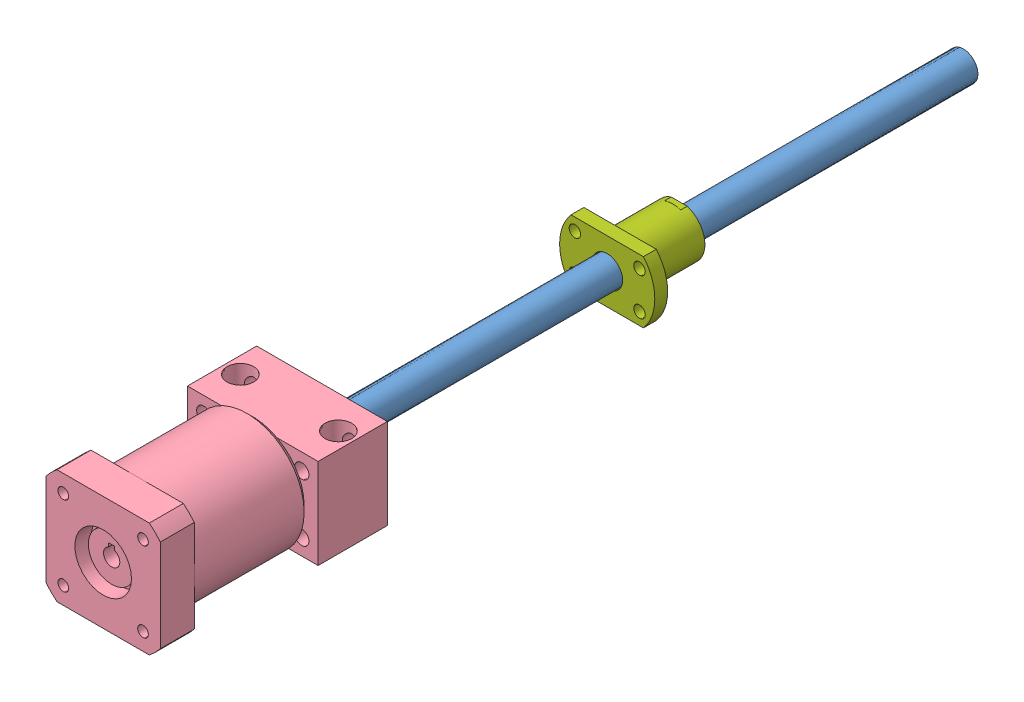
SolidWorks assembly PMBS12x5R_3FW_0_T10_U1_00_300_0_S, configuration Valor predeterminado. Lengths in mm.
Overall size (50.8 44.45 334.47).
8 component instances, 7 part files, 3 mates.
Components (placement in the parent):
- Screw_PMBS 12x5R-1: Screw_PMBS 12x5R [Valor predeterminado] at (0 0 -368.25) size (11.33 11.33 249)
- EndCode1_8-U1-1: EndCode1_8-U1 [Valor predeterminado] at (0 0 -119.25) x (0 0 1) z (-1 0 0) size (85.47 44.45 50.8)
  - Place Holder-1: Place Holder [Valor predeterminado] at origin size (0.38 0.51 0.51)
  - EndMachining_8-3K-1: EndMachining_8-3K [Valor predeterminado] x (0 0 1) z (-1 0 0) size (8 8 50.8)
  - EZM_EZM-1008-17-1: EZM_EZM-1008-17 [Valor predeterminado] at (27.305 -17.4498 25.4) x (0 0 -1) z (1 0 0) size (50.8 44.45 85.09)
  - LockNut(1)_N-00.8-1: LockNut(1)_N-00.8 [Valor predeterminado] at (28.8798 0 0) x (1 0 0) z (0 0.998865 0.047634) size (7.05 16.48 14.68)
  - Spacer-1: Spacer [Valor predeterminado] at origin size (28.88 9.91 9.91)
- Nut_MBN12x5R-3FW-1: Nut_MBN12x5R-3FW [Valor predeterminado] at (0 0 -229.75) x (0 0 -1) z (1 0 0) size (28 24 37)
Mates (geometry in assembly coordinates):
- Concêntrico1: concentric aligned: cylinder of Screw_PMBS 12x5R-1 through (0 0 -119.25) axis (0 0 -1) radius 5.665; cylinder of EndCode1_8-U1-1/EndMachining_8-3K-1 through (0 0 -119.25) axis (0 0 -1) radius 3.175
- Coincidente1: coincident anti-aligned: plane of Screw_PMBS 12x5R-1 through (0 0 -119.25) normal (0 0 1); plane of EndCode1_8-U1-1/EndMachining_8-3K-1 through (0 0 -119.25) normal (0 0 -1)
- Concêntrico2: concentric anti-aligned: cylinder of Screw_PMBS 12x5R-1 through (0 0 -119.25) axis (0 0 -1) radius 5.665; cylinder of Nut_MBN12x5R-3FW-1 through (0 0 -257.75) axis (0 0 1) radius 6
